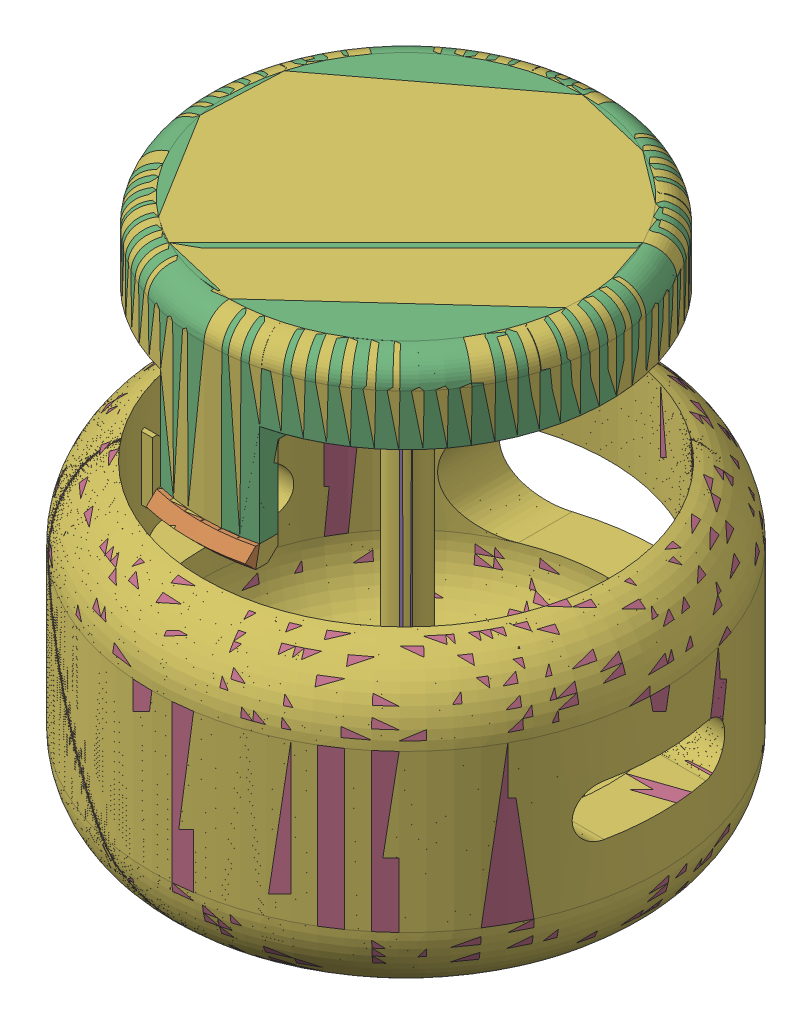
SolidWorks assembly button_comp, configuration 默认. Lengths in mm.
Overall size (20 21 20).
4 component instances, 4 part files, 2 mates.
Components (placement in the parent):
- button_cap-1: button_cap [默认] at (-0.0577 -1.8301 0) size (15.9 7.8 17) (hidden)
- button_shell-1: button_shell [默认] at (-3.9354 -15.8301 2.7704) size (20 12 20) (hidden)
- button_connect-1: button_connect [默认] at origin size (1.5 17.7 1.5) (hidden)
- button_print-1: button_print [默认] at origin size (20 21 20)
Mates (geometry in assembly coordinates):
- 同心1: concentric aligned: circle of button_cap-1; circle of button_shell-1
- 距离1: distance = 20 mm aligned: plane of button_cap-1 through (-0.0577 5.1699 0) normal (0 1 0); plane of button_shell-1 through (-0.0577 -14.8301 0) normal (0 1 0)
